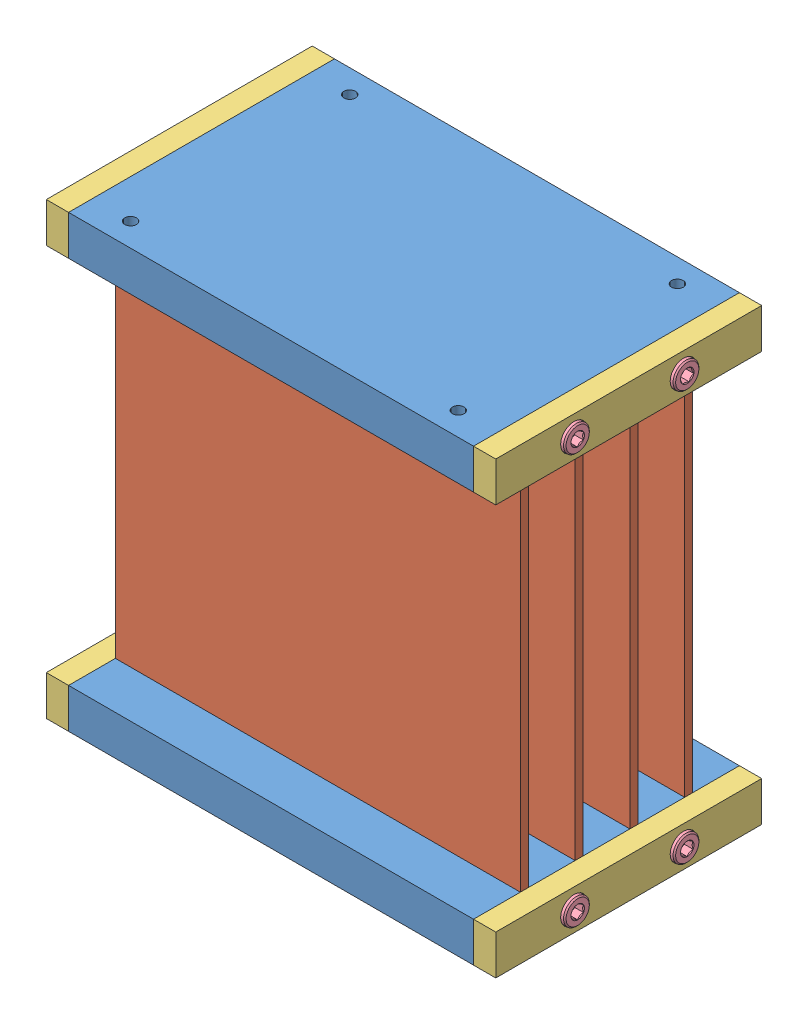
SolidWorks assembly STACK_SHELVES_ASSEMBLY, configuration Default. Lengths in mm.
Overall size (97.89 96 56.8).
18 component instances, 4 part files, 44 mates.
Components (placement in the parent):
- PCB_SHELF-1: PCB_SHELF [Default] at (-4.1696 1.9377 23.7027) x (0 1 0) z (1 0 0) size (8.5 56.8 86.5)
- FAKE_PCB-1: FAKE_PCB [Default] at (82.3304 4.4377 33.7027) x (0 1 0) z (1 0 0) size (91 1.7 86.5)
- FAKE_PCB-2: FAKE_PCB [Default] at (82.3304 4.4377 45.4027) x (0 1 0) z (1 0 0) size (91 1.7 86.5)
- FAKE_PCB-3: FAKE_PCB [Default] at (82.3304 4.4377 57.1027) x (0 1 0) z (1 0 0) size (91 1.7 86.5)
- FAKE_PCB-4: FAKE_PCB [Default] at (82.3304 4.4377 68.8027) x (0 1 0) z (1 0 0) size (91 1.7 86.5)
- PCB_SHELF-2: PCB_SHELF [Default] at (82.3304 97.9377 23.7027) x (0 -1 0) z (-1 0 0) size (8.5 56.8 86.5)
- PCB_SHELF_ENDS-1: PCB_SHELF_ENDS [Default] at (-4.1696 97.9377 80.5027) x (0 -1 0) z (-1 0 0) size (8.5 56.8 4.75)
- PCB_SHELF_ENDS-2: PCB_SHELF_ENDS [Default] at (-4.1696 10.4377 80.5027) x (0 -1 0) z (-1 0 0) size (8.5 56.8 4.75)
- PCB_SHELF_ENDS-3: PCB_SHELF_ENDS [Default] at (82.3304 89.4377 80.5027) x (0 1 0) z (1 0 0) size (8.5 56.8 4.75)
- PCB_SHELF_ENDS-4: PCB_SHELF_ENDS [Default] at (82.3304 1.9377 80.5027) x (0 1 0) z (1 0 0) size (8.5 56.8 4.75)
- M3_6mm_SCREW-1: M3_6mm_SCREW [91292A111] at (78.8804 93.6877 63.8027) x (0 -0.842846 0.538155) z (-1 0 0) size (5.5 5.5 9.19)
- M3_6mm_SCREW-2: M3_6mm_SCREW [91292A111] at (78.8804 93.6877 40.4027) x (0 0.66223 0.749301) z (-1 0 0) size (5.5 5.5 9.19)
- M3_6mm_SCREW-3: M3_6mm_SCREW [91292A111] at (78.8804 6.1877 63.8027) x (0 0 1) z (-1 0 0) size (5.5 5.5 9.19)
- M3_6mm_SCREW-4: M3_6mm_SCREW [91292A111] at (78.8804 6.1877 40.4027) x (0 0 1) z (-1 0 0) size (5.5 5.5 9.19)
- M3_6mm_SCREW-5: M3_6mm_SCREW [91292A111] at (-0.7196 93.6877 40.4027) x (0 0 -1) z (1 0 0) size (5.5 5.5 9.19)
- M3_6mm_SCREW-6: M3_6mm_SCREW [91292A111] at (-0.7196 93.6877 63.8027) x (0 0 -1) z (1 0 0) size (5.5 5.5 9.19)
- M3_6mm_SCREW-7: M3_6mm_SCREW [91292A111] at (-0.7196 6.1877 40.4027) x (0 0 -1) z (1 0 0) size (5.5 5.5 9.19)
- M3_6mm_SCREW-8: M3_6mm_SCREW [91292A111] at (-0.7196 6.1877 63.8027) x (0 0 -1) z (1 0 0) size (5.5 5.5 9.19)
Mates (geometry in assembly coordinates):
- Coincident10: coincident anti-aligned: plane of PCB_SHELF-1 through (82.3304 4.4377 35.4027) normal (0 1 0); plane of FAKE_PCB-1 through (82.3304 4.4377 35.4027) normal (0 -1 0)
- Coincident11: coincident anti-aligned: plane of PCB_SHELF-1 through (82.3304 4.4377 33.7027) normal (0 0 1); plane of FAKE_PCB-1 through (82.3304 4.4377 33.7027) normal (0 0 -1)
- Coincident12: coincident aligned: plane of PCB_SHELF-1 through (82.3304 1.9377 23.7027) normal (1 0 0); plane of FAKE_PCB-1 through (82.3304 95.4377 35.4027) normal (1 0 0)
- Coincident13: coincident anti-aligned: plane of PCB_SHELF-1 through (82.3304 4.4377 47.1027) normal (0 1 0); plane of FAKE_PCB-2 through (82.3304 4.4377 47.1027) normal (0 -1 0)
- Coincident14: coincident anti-aligned: plane of PCB_SHELF-1 through (82.3304 4.4377 45.4027) normal (0 0 1); plane of FAKE_PCB-2 through (82.3304 4.4377 45.4027) normal (0 0 -1)
- Coincident15: coincident aligned: plane of PCB_SHELF-1 through (-4.1696 1.9377 23.7027) normal (-1 0 0); plane of FAKE_PCB-2 through (-4.1696 4.4377 47.1027) normal (-1 0 0)
- Coincident16: coincident anti-aligned: plane of PCB_SHELF-1 through (82.3304 4.4377 58.8027) normal (0 1 0); plane of FAKE_PCB-3 through (82.3304 4.4377 58.8027) normal (0 -1 0)
- Coincident17: coincident anti-aligned: plane of PCB_SHELF-1 through (82.3304 4.4377 57.1027) normal (0 0 1); plane of FAKE_PCB-3 through (82.3304 4.4377 57.1027) normal (0 0 -1)
- Coincident18: coincident aligned: plane of PCB_SHELF-1 through (-4.1696 1.9377 23.7027) normal (-1 0 0); plane of FAKE_PCB-3 through (-4.1696 4.4377 58.8027) normal (-1 0 0)
- Coincident19: coincident anti-aligned: plane of PCB_SHELF-1 through (82.3304 4.4377 70.5027) normal (0 1 0); plane of FAKE_PCB-4 through (82.3304 4.4377 70.5027) normal (0 -1 0)
- Coincident20: coincident anti-aligned: plane of PCB_SHELF-1 through (82.3304 4.4377 68.8027) normal (0 0 1); plane of FAKE_PCB-4 through (82.3304 4.4377 68.8027) normal (0 0 -1)
- Coincident21: coincident aligned: plane of PCB_SHELF-1 through (-4.1696 1.9377 23.7027) normal (-1 0 0); plane of FAKE_PCB-4 through (-4.1696 4.4377 70.5027) normal (-1 0 0)
- Coincident22: coincident anti-aligned: plane of FAKE_PCB-4 through (-4.1696 95.4377 70.5027) normal (0 1 0); plane of PCB_SHELF-2 through (-4.1696 95.4377 70.5027) normal (0 -1 0)
- Coincident23: coincident aligned: plane of FAKE_PCB-4 through (82.3304 95.4377 70.5027) normal (1 0 0); plane of PCB_SHELF-2 through (82.3304 97.9377 23.7027) normal (1 0 0)
- Coincident24: coincident aligned: plane of FAKE_PCB-1 through (82.3304 95.4377 35.4027) normal (1 0 0); plane of PCB_SHELF-2 through (82.3304 97.9377 23.7027) normal (1 0 0)
- Coincident25: coincident anti-aligned: plane of FAKE_PCB-1 through (82.3304 4.4377 35.4027) normal (0 0 1); plane of PCB_SHELF-2 through (-4.1696 89.4377 35.4027) normal (0 0 -1)
- Concentric1: concentric aligned: cylinder of PCB_SHELF-1 through (82.3304 6.1877 63.8027) axis (1 0 0) radius 1.25; cylinder of PCB_SHELF_ENDS-4 through (87.0804 6.1877 63.8027) axis (1 0 0) radius 1.7
- Coincident26: coincident anti-aligned: plane of PCB_SHELF-1 through (82.3304 1.9377 23.7027) normal (1 0 0); plane of PCB_SHELF_ENDS-4 through (82.3304 1.9377 80.5027) normal (-1 0 0)
- Concentric2: concentric aligned: cylinder of PCB_SHELF-1 through (82.3304 6.1877 40.4027) axis (1 0 0) radius 1.25; cylinder of PCB_SHELF_ENDS-4 through (87.0804 6.1877 40.4027) axis (1 0 0) radius 1.7
- Coincident27: coincident anti-aligned: plane of PCB_SHELF-2 through (82.3304 97.9377 23.7027) normal (1 0 0); plane of PCB_SHELF_ENDS-3 through (82.3304 89.4377 80.5027) normal (-1 0 0)
- Concentric3: concentric aligned: cylinder of PCB_SHELF-2 through (82.3304 93.6877 63.8027) axis (1 0 0) radius 1.25; cylinder of PCB_SHELF_ENDS-3 through (87.0804 93.6877 63.8027) axis (1 0 0) radius 1.7
- Concentric4: concentric aligned: cylinder of PCB_SHELF-2 through (82.3304 93.6877 40.4027) axis (1 0 0) radius 1.25; cylinder of PCB_SHELF_ENDS-3 through (87.0804 93.6877 40.4027) axis (1 0 0) radius 1.7
- Coincident28: coincident anti-aligned: plane of PCB_SHELF-1 through (-4.1696 1.9377 23.7027) normal (-1 0 0); plane of PCB_SHELF_ENDS-2 through (-4.1696 10.4377 80.5027) normal (1 0 0)
- Concentric5: concentric aligned: cylinder of PCB_SHELF-1 through (-4.1696 6.1877 63.8027) axis (-1 0 0) radius 1.25; cylinder of PCB_SHELF_ENDS-2 through (-8.9196 6.1877 63.8027) axis (-1 0 0) radius 1.7
- Concentric6: concentric aligned: cylinder of PCB_SHELF-1 through (-4.1696 6.1877 40.4027) axis (-1 0 0) radius 1.25; cylinder of PCB_SHELF_ENDS-2 through (-8.9196 6.1877 40.4027) axis (-1 0 0) radius 1.7
- Coincident29: coincident anti-aligned: plane of PCB_SHELF-2 through (-4.1696 97.9377 23.7027) normal (-1 0 0); plane of PCB_SHELF_ENDS-1 through (-4.1696 97.9377 80.5027) normal (1 0 0)
- Concentric7: concentric aligned: cylinder of PCB_SHELF-2 through (-4.1696 93.6877 63.8027) axis (-1 0 0) radius 1.25; cylinder of PCB_SHELF_ENDS-1 through (-8.9196 93.6877 63.8027) axis (-1 0 0) radius 1.7
- Concentric8: concentric aligned: cylinder of PCB_SHELF-2 through (-4.1696 93.6877 40.4027) axis (-1 0 0) radius 1.25; cylinder of PCB_SHELF_ENDS-1 through (-8.9196 93.6877 40.4027) axis (-1 0 0) radius 1.7
- Concentric9: concentric anti-aligned: circle of PCB_SHELF_ENDS-3; circle of M3_6mm_SCREW-1
- Coincident31: coincident anti-aligned: plane of PCB_SHELF_ENDS-3 through (84.8804 93.6877 63.8027) normal (1 0 0); plane of M3_6mm_SCREW-1 through (84.8804 93.6877 63.8027) normal (-1 0 0)
- Concentric10: concentric anti-aligned: circle of PCB_SHELF_ENDS-3; circle of M3_6mm_SCREW-2
- Coincident32: coincident anti-aligned: plane of PCB_SHELF_ENDS-3 through (84.8804 93.6877 40.4027) normal (1 0 0); plane of M3_6mm_SCREW-2 through (84.8804 93.6877 40.4027) normal (-1 0 0)
- Concentric11: concentric anti-aligned: circle of PCB_SHELF_ENDS-4; circle of M3_6mm_SCREW-4
- Coincident33: coincident anti-aligned: plane of PCB_SHELF_ENDS-4 through (84.8804 6.1877 40.4027) normal (1 0 0); plane of M3_6mm_SCREW-4 through (84.8804 6.1877 40.4027) normal (-1 0 0)
- Concentric12: concentric anti-aligned: circle of PCB_SHELF_ENDS-4; circle of M3_6mm_SCREW-3
- Coincident34: coincident anti-aligned: plane of PCB_SHELF_ENDS-4 through (84.8804 6.1877 63.8027) normal (1 0 0); plane of M3_6mm_SCREW-3 through (84.8804 6.1877 63.8027) normal (-1 0 0)
- Concentric13: concentric anti-aligned: circle of PCB_SHELF_ENDS-2; circle of M3_6mm_SCREW-8
- Coincident36: coincident anti-aligned: plane of PCB_SHELF_ENDS-2 through (-6.7196 6.1877 63.8027) normal (-1 0 0); plane of M3_6mm_SCREW-8 through (-6.7196 6.1877 63.8027) normal (1 0 0)
- Concentric14: concentric anti-aligned: circle of PCB_SHELF_ENDS-2; circle of M3_6mm_SCREW-7
- Coincident37: coincident anti-aligned: plane of PCB_SHELF_ENDS-2 through (-6.7196 6.1877 40.4027) normal (-1 0 0); plane of M3_6mm_SCREW-7 through (-6.7196 6.1877 40.4027) normal (1 0 0)
- Concentric15: concentric anti-aligned: circle of PCB_SHELF_ENDS-1; circle of M3_6mm_SCREW-6
- Coincident38: coincident anti-aligned: plane of PCB_SHELF_ENDS-1 through (-6.7196 93.6877 63.8027) normal (-1 0 0); plane of M3_6mm_SCREW-6 through (-6.7196 93.6877 63.8027) normal (1 0 0)
- Concentric16: concentric anti-aligned: circle of PCB_SHELF_ENDS-1; circle of M3_6mm_SCREW-5
- Coincident39: coincident anti-aligned: plane of PCB_SHELF_ENDS-1 through (-6.7196 93.6877 40.4027) normal (-1 0 0); plane of M3_6mm_SCREW-5 through (-6.7196 93.6877 40.4027) normal (1 0 0)
